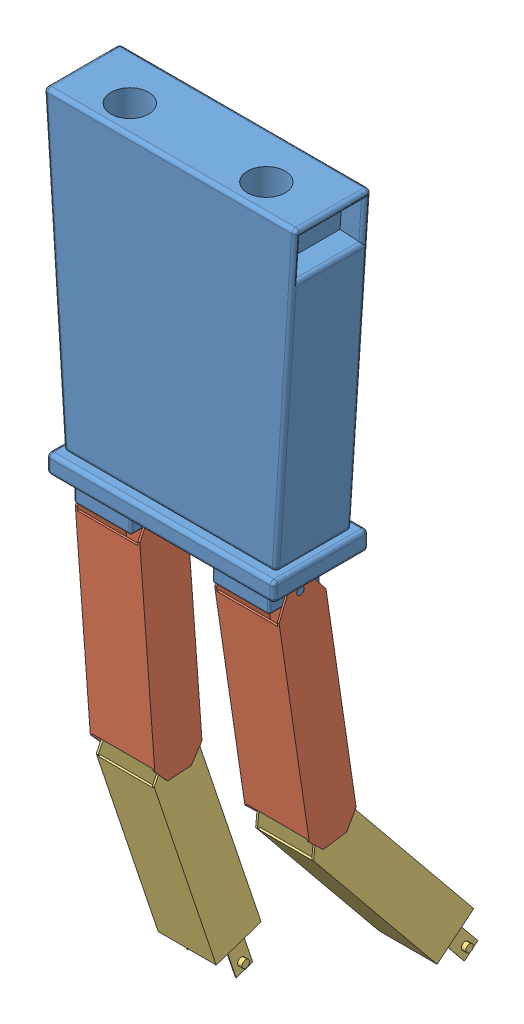
SolidWorks assembly Sadia Chest and legs Assembly, configuration Default. Lengths in mm.
Overall size (66.36 208.16 61.49).
5 component instances, 3 part files, 8 mates.
Components (placement in the parent):
- Sadia Chest edit-1: Sadia Chest edit [Default] at (43.6078 49.4018 52.306) size (66.36 91.67 25)
- Sadia thigh-1: Sadia thigh [Default] at (62.3377 4.8233 64.3294) x (1 0 0) z (0 -0.989295 -0.145932) size (17 12.48 63.77)
- Sadia thigh-2: Sadia thigh [Default] at (25.9047 4.7846 64.6813) x (-1 0 0) z (0 -0.99736 -0.072621) size (17 12.48 63.77)
- Sadia leg-1: Sadia leg [Default] at (62.4877 -50.9865 55.7069) x (1 0 0) z (0 -0.774812 -0.632192) size (15.3 12.48 62.71)
- Sadia leg-2: Sadia leg [Default] at (26.0547 -51.606 60.3881) x (1 0 0) z (0 -0.948201 -0.317671) size (15.3 12.48 62.71)
Mates (geometry in assembly coordinates):
- Concentric2: concentric: cylinder of Sadia Chest edit-1 through (70.8377 9.5719 65.0299) axis (-1 0 0) radius 1; cylinder of Sadia thigh-1 through (53.8377 9.5719 65.0299) axis (1 0 0) radius 1
- Coincident5: coincident: circle of Sadia Chest edit-1; circle of Sadia thigh-1
- Concentric3: concentric: cylinder of Sadia Chest edit-1 through (16.3778 9.5719 65.0299) axis (1 0 0) radius 1; cylinder of Sadia thigh-2 through (34.4047 9.5719 65.0299) axis (-1 0 0) radius 1
- Coincident7: coincident: circle of Sadia Chest edit-1; circle of Sadia thigh-2
- Concentric4: concentric: cylinder of Sadia thigh-2 through (18.9047 -50.892 60.6273) axis (-1 0 0) radius 1; cylinder of Sadia leg-2 through (18.4047 -50.892 60.6273) axis (1 0 0) radius 1
- Coincident8: coincident: circle of Sadia thigh-2; circle of Sadia leg-2
- Concentric5: concentric: cylinder of Sadia thigh-1 through (55.3377 -50.4031 56.1829) axis (-1 0 0) radius 1; cylinder of Sadia leg-1 through (54.8377 -50.4031 56.1829) axis (1 0 0) radius 1
- Coincident10: coincident: circle of Sadia thigh-1; circle of Sadia leg-1
